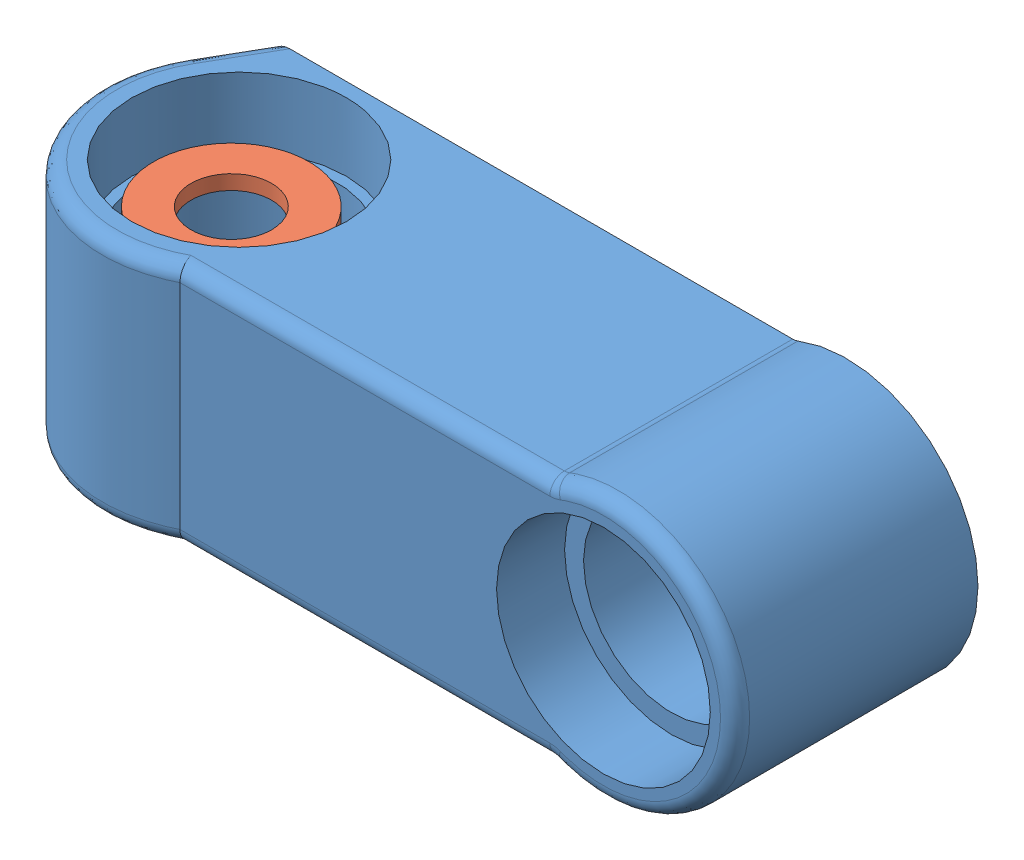
SolidWorks assembly HUB CENTER, configuration Default. Lengths in mm.
Overall size (77.6 27.1 26.55).
2 component instances, 2 part files, 0 mates.
Components (placement in the parent):
- HUB CENTER-1: HUB CENTER [Default] at (0.7972 6.0767 -0.0017) size (77.6 27.1 26.55)
- M8 WASHER_1-1: M8 WASHER_1 [Default] at (0 14 12.5) x (1 0 0) z (0 -1 0) size (16 16 1.5)
